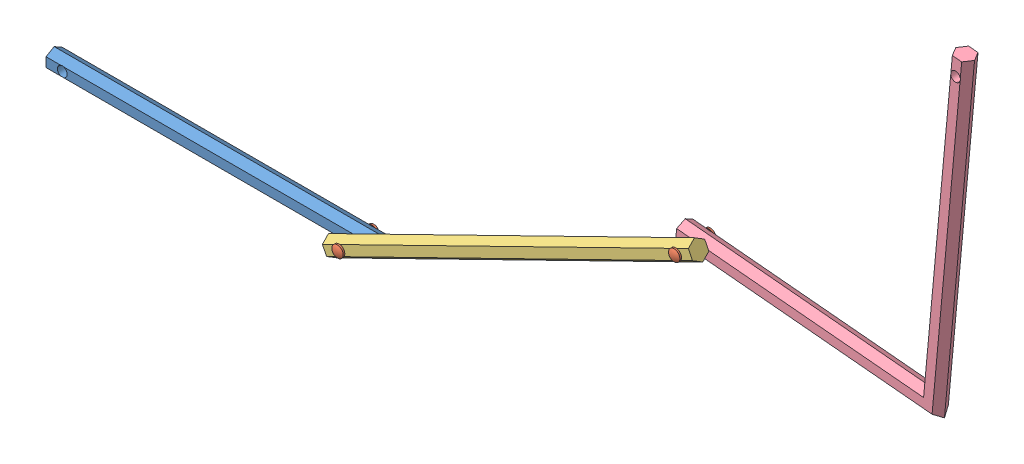
SolidWorks assembly Assem3, configuration Valor predeterminado. Lengths in mm.
Overall size (564.57 305.12 24.2).
5 component instances, 4 part files, 8 mates.
Components (placement in the parent):
- Eixo 1-1: Eixo 1 [Valor predeterminado] at (-74.4627 23.487 200) size (200 11.55 10)
- pino-1: pino [Valor predeterminado] at (15.5373 23.487 205.1) x (1 0 0) z (0 1 0) size (7 24.2 7)
- Eixo 2 250mm-1: Eixo 2 250mm [Valor predeterminado] at (118.8041 74.093 210.2) x (-0.897972 -0.440052 0) z (0 0 1) size (250 11.55 10)
- Eixo 3 em L-1: Eixo 3 em L [Valor predeterminado] at (375.1411 205.1549 200) x (0.99574 -0.092202 0) z (0.092202 0.99574 0) size (160.77 10 200)
- pino-2: pino [Valor predeterminado] at (222.0709 124.699 205.1) x (1 0 0) z (0 1 0) size (7 24.2 7)
Mates (geometry in assembly coordinates):
- Concentric1: concentric: cylinder of assembly; cylinder of assembly; cylinder of Eixo 1-1 through (15.5373 23.487 195) axis (0 0 1) radius 3; cylinder of pino-1 through (15.5373 23.487 199.1492) axis (0 0 -1) radius 3
- Concentric2: concentric: cylinder of assembly; cylinder of assembly; cylinder of pino-1 through (15.5373 23.487 199.1492) axis (0 0 -1) radius 3; cylinder of Eixo 2 250mm-1 through (15.5373 23.487 205.2) axis (0 0 1) radius 3
- Coincident1: coincident: plane of assembly; plane of assembly; plane of pino-1 through (15.5373 23.487 215.2) normal (0 0 -1); plane of Eixo 2 250mm-1 through (7.8279 16.4942 215.2) normal (0 0 1)
- Coincident3: coincident: plane of assembly; plane of assembly; plane of Eixo 1-1 through (25.5373 20.6002 195) normal (0 0 -1); plane of pino-1 through (15.5373 23.487 195) normal (0 0 1)
- Concentric3: concentric: cylinder of assembly; cylinder of assembly; cylinder of Eixo 2 250mm-1 through (222.0709 124.699 205.2) axis (0 0 1) radius 3; cylinder of Eixo 3 em L-1 through (222.0709 124.699 205.0001) axis (0 0 -1) radius 3
- Concentric4: concentric: cylinder of assembly; cylinder of assembly; cylinder of Eixo 2 250mm-1 through (222.0709 124.699 205.2) axis (0 0 1) radius 3; cylinder of pino-2 through (222.0709 124.699 199.1492) axis (0 0 -1) radius 3
- Coincident4: coincident: plane of assembly; plane of assembly; plane of Eixo 2 250mm-1 through (7.8279 16.4942 215.2) normal (0 0 1); plane of pino-2 through (222.0709 124.699 215.2) normal (0 0 -1)
- Coincident5: coincident: plane of assembly; plane of assembly; plane of Eixo 3 em L-1 through (387.2357 304.4628 195) normal (0 0 -1); plane of pino-2 through (222.0709 124.699 195) normal (0 0 1)
